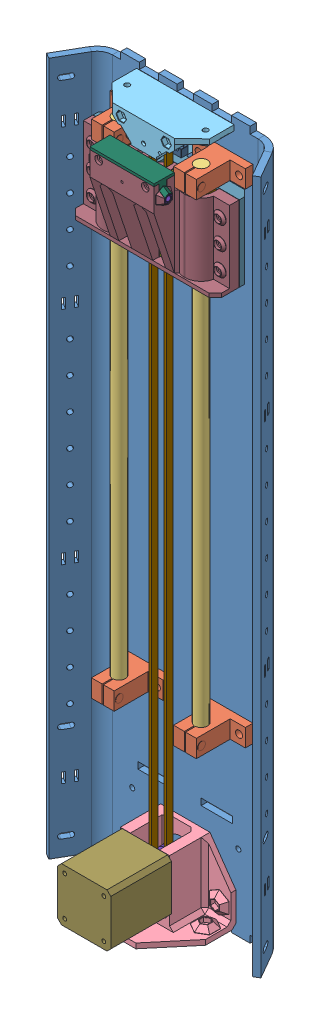
SolidWorks assembly axis-assembly, configuration Default. Lengths in mm.
Overall size (169.64 560 85).
27 component instances, 18 part files, 32 mates.
Components (placement in the parent):
- acrylic-wall-1: acrylic-wall [Default] x (0 0 -1) z (1 0 0) size (32.5 560 169.64)
- Rod-clamp-sk10-1: Rod-clamp-sk10 [Default] at (0 -96 0) x (0 0 -1) z (1 0 0) size (32.8 14 42)
- Rod-clamp-sk10-2: Rod-clamp-sk10 [Default] at (0 962 0) x (0 0 -1) z (-1 0 0) size (32.8 14 42)
- Rod-clamp-sk10-3: Rod-clamp-sk10 [Default] at (0 -479 0) x (0 0 -1) z (1 0 0) size (32.8 14 42)
- Rod-clamp-sk10-4: Rod-clamp-sk10 [Default] at (65 -479 0) x (0 0 -1) z (1 0 0) size (32.8 14 42)
- smooth-rod-1: smooth-rod [Default] at (0 -110 0) x (0 0 -1) z (1 0 0) size (10 400 10)
- smooth-rod-2: smooth-rod [Default] at (-65 -110 0) x (0 0 -1) z (1 0 0) size (10 400 10)
- motor-bracket-1: motor-bracket [Default] at (0 -90 0) x (0 0 -1) z (1 0 0) size (54 55.2 80)
- axis-idler-assembly-1: axis-idler-assembly [Default] at (0 -90 0) size (77.25 525.6 33)
  - Idler-bracket-1: Idler-bracket [Default] x (0 0 -1) z (1 0 0) size (33 34.75 77.25)
  - idler-bearing-1: idler-bearing [Default] x (0 0 -1) z (1 0 0) size (4 10 10)
  - idler-bearing-2: idler-bearing [Default] at (0 0 22.4) x (0 0 -1) z (1 0 0) size (4 10 10)
  - idler-rod-1: idler-rod [Default] x (0 0 -1) z (1 0 0) size (25 5 5)
  - timing-pulley-1: timing-pulley [Default] at (-499.0739 344.0495 0) x (0 0 -1) z (0.355713 -0.934595 0) size (16 17 17)
  - Belt-1: Belt [Default] at (0 0 0.26) x (0 0 -1) z (1 0 0) size (5 516.7 13.7)
  - KW-10-Mechanical-endstop-1: KW-10-Mechanical-endstop [Default] at (0 521.5 -208.15) x (-1 0 0) z (0 0 1) size (12.8 11 5.7)
  - magnet-4-15-5-1: magnet-4-15-5 [Default] at (-16 528 -194.5) x (0.988109 0 -0.153754) z (-0.153754 0 -0.988109) size (15 5 15)
- motor-1: motor [Default] at (0 -87 0) x (0 0 -1) z (1 0 0) size (72 42 42)
- timing-pulley-1: timing-pulley [Default] at (0 -590 0) x (0 0 -1) z (1 0 0) size (16 17 17)
- axis-carriage-assembly-1: axis-carriage-assembly [Default] at (0.0738 365.6127 -219.9038) x (-0.999996 0 -0.002957) z (-0.002957 0 0.999996) size (116 72 45.5)
  - carriage-front-lm10luu-1: carriage-front-lm10luu [Default] at (0 -60 25) size (116 70 34.75)
  - carriage-back-lm10luu-1: carriage-back-lm10luu [Default] at (0 -60 25) size (116 60 16.5)
  - standoff-cover-lm10luu-1: standoff-cover-lm10luu [Default] at (0 -60 25) size (60 9.59 16)
  - belt-wedge-lm10luu-1: belt-wedge-lm10luu [Default] at (0 -60 25) size (9.85 57 8.25)
  - standoff-60mm-1: standoff-60mm [Default] at (0 -52.5552 23) size (60 6.68 6)
  - Bearing-linear-LM10LUU-1: Bearing-linear-LM10LUU [Default] at (32.5 -30 25) size (19 55 19)
  - Bearing-linear-LM10LUU-2: Bearing-linear-LM10LUU [Default] at (-32.4997 -30 24.8078) size (19 55 19)
Mates (geometry in assembly coordinates):
- Coincident1: coincident anti-aligned: plane of acrylic-wall-1 through (-57.685 -90 -215) normal (0 0 1); plane of Rod-clamp-sk10-1 through (-53.5 426 -215) normal (0 0 -1)
- Concentric1: concentric aligned: cylinder of acrylic-wall-1 through (-16.5 433 -215) axis (0 0 1) radius 3; cylinder of Rod-clamp-sk10-1 through (-16.5 433 -220) axis (0 0 1) radius 2.75
- Concentric2: concentric aligned: cylinder of acrylic-wall-1 through (-48.5 433 -215) axis (0 0 1) radius 3; cylinder of Rod-clamp-sk10-1 through (-48.5 433 -220) axis (0 0 1) radius 2.75
- Coincident2: coincident anti-aligned: plane of acrylic-wall-1 through (-57.685 -90 -215) normal (0 0 1); plane of Rod-clamp-sk10-3 through (-53.5 43 -215) normal (0 0 -1)
- Concentric3: concentric aligned: cylinder of acrylic-wall-1 through (-16.5 50 -215) axis (0 0 1) radius 3; cylinder of Rod-clamp-sk10-3 through (-16.5 50 -220) axis (0 0 1) radius 2.75
- Concentric4: concentric aligned: cylinder of acrylic-wall-1 through (-48.5 50 -215) axis (0 0 1) radius 3; cylinder of Rod-clamp-sk10-3 through (-48.5 50 -220) axis (0 0 1) radius 2.75
- Coincident8: coincident anti-aligned: plane of Rod-clamp-sk10-1 through (0 -96 0) normal (1 0 0); plane of Rod-clamp-sk10-2 through (0 962 0) normal (-1 0 0)
- Coincident9: coincident anti-aligned: plane of acrylic-wall-1 through (-57.685 -90 -215) normal (0 0 1); plane of Rod-clamp-sk10-2 through (53.5 440 -215) normal (0 0 -1)
- Coincident10: coincident aligned: plane of Rod-clamp-sk10-1 through (0 440 0) normal (0 1 0); plane of Rod-clamp-sk10-2 through (0 440 0) normal (0 1 0)
- Concentric6: concentric anti-aligned: cylinder of Rod-clamp-sk10-2 through (32.5 440 -195) axis (0 -1 0) radius 5; cylinder of Rod-clamp-sk10-4 through (32.5 43 -195) axis (0 1 0) radius 5
- Coincident11: coincident aligned: plane of Rod-clamp-sk10-3 through (0 57 0) normal (0 1 0); plane of Rod-clamp-sk10-4 through (65 57 0) normal (0 1 0)
- Coincident12: coincident anti-aligned: plane of acrylic-wall-1 through (-57.685 -90 -215) normal (0 0 1); plane of Rod-clamp-sk10-4 through (11.5 43 -215) normal (0 0 -1)
- Concentric7: concentric anti-aligned: cylinder of Rod-clamp-sk10-4 through (32.5 43 -195) axis (0 1 0) radius 5; cylinder of smooth-rod-1 through (32.5 440 -195) axis (0 -1 0) radius 5
- Coincident13: coincident aligned: plane of Rod-clamp-sk10-2 through (0 440 0) normal (0 1 0); plane of smooth-rod-1 through (32.5 440 -195) normal (0 1 0)
- Concentric8: concentric anti-aligned: cylinder of Rod-clamp-sk10-3 through (-32.5 43 -195) axis (0 1 0) radius 5; cylinder of smooth-rod-2 through (-32.5 440 -195) axis (0 -1 0) radius 5
- Coincident14: coincident aligned: plane of Rod-clamp-sk10-1 through (0 440 0) normal (0 1 0); plane of smooth-rod-2 through (-32.5 440 -195) normal (0 1 0)
- Coincident17: coincident anti-aligned: plane of acrylic-wall-1 through (0 0 0) normal (0 0 -1); plane of assembly through (0 0 0) normal (0 0 1)
- Coincident18: coincident aligned: plane of acrylic-wall-1 through (0 0 0) normal (1 0 0); plane of assembly through (0 0 0) normal (1 0 0)
- Coincident19: coincident aligned: plane of acrylic-wall-1; plane of assembly through (0 0 0) normal (0 1 0)
- Coincident20: coincident anti-aligned: plane of motor-bracket-1 through (0 -90 0) normal (0 0 -1); plane of assembly through (0 0 0) normal (0 0 1)
- Coincident21: coincident aligned: plane of motor-bracket-1 through (0 -90 0) normal (1 0 0); plane of assembly through (0 0 0) normal (1 0 0)
- Concentric9: concentric aligned: cylinder of acrylic-wall-1 through (-31 -75 -215) axis (0 0 1) radius 2; cylinder of motor-bracket-1 through (-31 -75 -220) axis (0 0 1) radius 2
- Coincident22: coincident aligned: plane of axis-idler-assembly-1 through (0 -90 0) normal (0 0 1); plane of assembly through (0 0 0) normal (0 0 1)
- Coincident23: coincident aligned: plane of axis-idler-assembly-1 through (0 -90 0) normal (1 0 0); plane of assembly through (0 0 0) normal (1 0 0)
- Concentric10: concentric anti-aligned: cylinder of acrylic-wall-1 through (17.75 453.5 -215) axis (0 0 -1) radius 2; cylinder of axis-idler-assembly-1/Idler-bracket-1 through (17.75 453.5 -220) axis (0 0 1) radius 2
- Coincident24: coincident aligned: plane of motor-1 through (0 -87 0) normal (1 0 0); plane of assembly through (0 0 0) normal (1 0 0)
- Coincident25: coincident anti-aligned: plane of motor-bracket-1 through (0 -90 -183) normal (0 0 1); plane of motor-1 through (0 -87 -183) normal (0 0 -1)
- Concentric11: concentric aligned: cylinder of motor-bracket-1 through (-15.5 -40.5 -211) axis (0 0 -1) radius 1.7; cylinder of motor-1 through (-15.5 -40.5 -135) axis (0 0 -1) radius 1.5
- Concentric12: concentric anti-aligned: cylinder of motor-1 through (0 -56 -207) axis (0 0 1) radius 2.5; cylinder of timing-pulley-1 through (0 -56 -190.5) axis (0 0 -1) radius 2.5
- Distance1: distance = 1 mm anti-aligned: plane of timing-pulley-1 through (0 -56 -199.24) normal (0 0 1); plane of axis-idler-assembly-1/Belt-1 through (0 444 -198.24) normal (0 0 -1)
- Concentric14: concentric aligned: cylinder of smooth-rod-1 through (32.5 440 -195) axis (0 -1 0) radius 5; cylinder of axis-carriage-assembly-1/Bearing-linear-LM10LUU-2 through (32.5 349.5681 -195) axis (0 -1 0) radius 5
- Concentric15: concentric aligned: cylinder of smooth-rod-2 through (-32.5 440 -195) axis (0 -1 0) radius 5; cylinder of axis-carriage-assembly-1/Bearing-linear-LM10LUU-1 through (-32.5 349.5681 -195) axis (0 -1 0) radius 5
